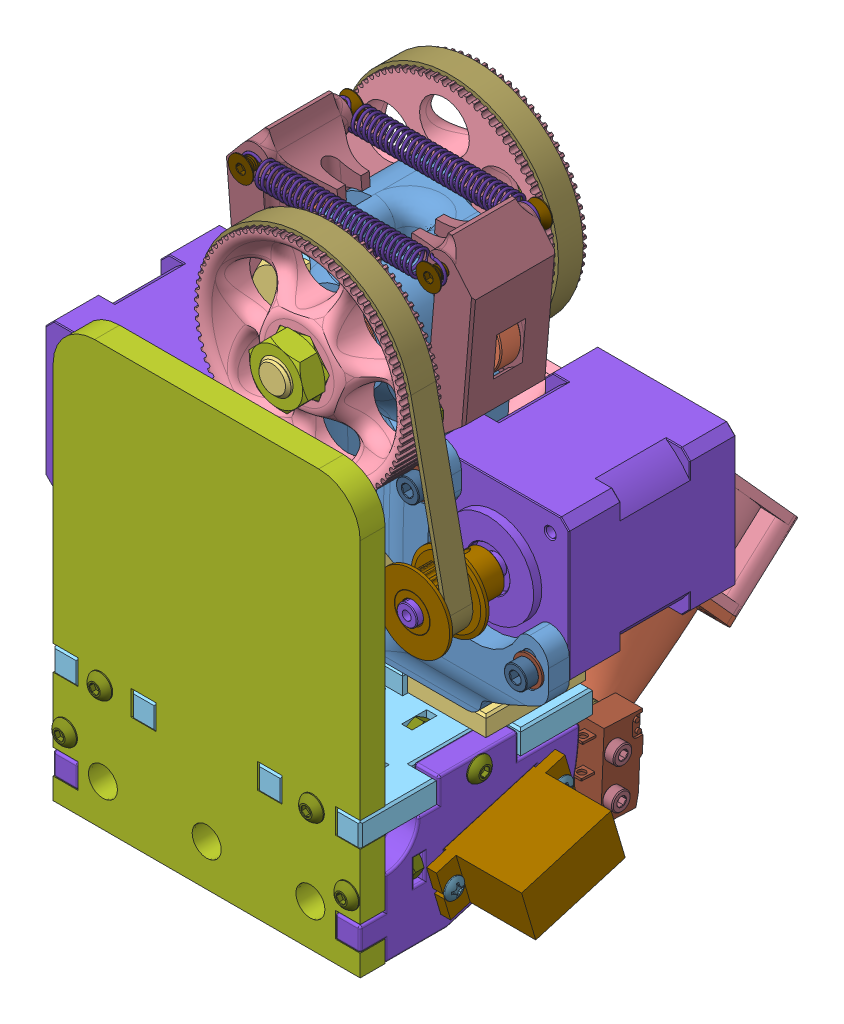
SolidWorks assembly XCarriageAssembly, configuration Default. Lengths in mm.
Overall size (108.39 160.46 126.11).
101 component instances, 38 part files, 22 mates.
Components (placement in the parent):
- IttyBittyDoubleExtruderAssembly-1: IttyBittyDoubleExtruderAssembly [Default] at origin size (106.39 98.03 74.25)
  - IttyBittyDoubleExtruderBlock-1: IttyBittyDoubleExtruderBlock [Default] at origin size (106.2 79.3 54.92)
  - Bearing-688-1: Bearing-688 [7804K117] at (-8 64.4888 10.5) size (16 16 5)
  - Bearing-688-2: Bearing-688 [7804K117] at (8 64.4888 16.5) size (16 16 5)
  - Bearing-688-3: Bearing-688 [7804K117] at (8 64.4888 -10.5) size (16 16 5)
  - Bearing-688-4: Bearing-688 [7804K117] at (-8 64.4888 -16.5) size (16 16 5)
  - HobbedBolt-1: HobbedBolt [Default] at (8 64.4888 -14) x (0.945139 -0.326669 0) z (0 0 1) size (14.66 12.7 56.13)
  - Parametric-Pulley-80-8-hex-1: Parametric-Pulley-80-8-hex [Default] at (8 64.4888 32) x (0.986927 0.161169 0) z (0 0 -1) size (50.4 50.4 9.47)
  - Spacer 1mm-1: Spacer 1mm [Default] at (8 64.4888 -14) size (13 13 1)
  - Spacer 2mm-1: Spacer 2mm [Default] at (8 64.4888 19) size (13 13 2)
  - HobbedBolt-2: HobbedBolt [Default] at (-8 64.4888 14) x (-0.397408 -0.917642 0) z (0 0 -1) size (14.66 12.7 56.13)
  - Parametric-Pulley-80-8-hex-2: Parametric-Pulley-80-8-hex [Default] at (-8 64.4888 -32) x (1 0 0) z (0 0 1) size (50.4 50.4 9.47)
  - Spacer 1mm-2: Spacer 1mm [Default] at (-8 64.4888 14) x (-0.923728 -0.383049 0) z (0 0 -1) size (13 13 1)
  - Spacer 2mm-2: Spacer 2mm [Default] at (-8 64.4888 -21) size (13 13 2)
  - 5-16-Nut-1: 5-16-Nut [Default] at (-8 64.4888 -30.3) size (14.66 12.7 5.2)
  - 5-16-Nut-2: 5-16-Nut [Default] at (8 64.4888 25.1) x (0.353886 0.935288 0) z (0 0 1) size (14.66 12.7 5.2)
  - 5-16-Nut-3: 5-16-Nut [Default] at (8 64.4888 30.3) x (0.969294 -0.245906 0) z (0 0 1) size (14.66 12.7 5.2)
  - 5-16-Nut-4: 5-16-Nut [Default] at (-8 64.4888 -35.5) x (0.948708 -0.316153 0) z (0 0 1) size (14.66 12.7 5.2)
  - NEMA14 Stepper Motor-1: NEMA14 Stepper Motor [Default] at (17.9692 8.8788 -30.1574) x (-1 0 0) z (0 1 0) size (36.32 61.75 35.05)
  - GT2_20tooth-1: GT2_20tooth [Default] at (35.4952 26.4048 12.75) x (0 0 1) z (-0.834274 -0.551351 0) size (17.5 18 18)
  - GT2_20tooth-2: GT2_20tooth [Default] at (-35.4952 26.4048 -12.75) x (0 0 -1) z (0.834274 -0.551351 0) size (17.5 18 18)
  - NEMA14 Stepper Motor-2: NEMA14 Stepper Motor [Default] at (-17.9692 8.8788 30.1574) x (1 0 0) z (0 1 0) size (36.32 61.75 35.05)
  - M3x10HexCapScrew-1: M3x10HexCapScrew [91290A115] at (22.5 13.4 5.45) x (-0.709862 0.70434 0) z (0 0 -1) size (5.5 5.5 13.21)
  - M3Washer-1: M3Washer [91166A210] at (22.5 13.4 15) x (0.895294 -0.445476 0) z (0 0 -1) size (7 7 0.45)
  - M3Washer-12: M3Washer [91166A210] at (-22.5 13.4 -15) x (-0.895294 -0.445476 0) z (0 0 1) size (7 7 0.45)
  - M3x10HexCapScrew-5: M3x10HexCapScrew [91290A115] at (-22.5 13.4 -5.45) x (0.709862 0.70434 0) z (0 0 1) size (5.5 5.5 13.21)
  - M3Washer-13: M3Washer [91166A210] at (22.5 39.4 15) x (0.895294 -0.445476 0) z (0 0 -1) size (7 7 0.45)
  - M3Washer-14: M3Washer [91166A210] at (48.5 13.4 15) x (0.895294 -0.445476 0) z (0 0 -1) size (7 7 0.45)
  - M3x10HexCapScrew-6: M3x10HexCapScrew [91290A115] at (22.5 39.4 5.45) x (-0.709862 0.70434 0) z (0 0 -1) size (5.5 5.5 13.21)
  - M3x10HexCapScrew-7: M3x10HexCapScrew [91290A115] at (48.5 13.4 5.45) x (-0.709862 0.70434 0) z (0 0 -1) size (5.5 5.5 13.21)
  - M3Washer-16: M3Washer [91166A210] at (-22.5 39.4 -15) x (-0.895294 -0.445476 0) z (0 0 1) size (7 7 0.45)
  - M3Washer-17: M3Washer [91166A210] at (-48.5 13.4 -15) x (-0.895294 -0.445476 0) z (0 0 1) size (7 7 0.45)
  - M3x10HexCapScrew-9: M3x10HexCapScrew [91290A115] at (-22.5 39.4 -5.45) x (0.709862 0.70434 0) z (0 0 1) size (5.5 5.5 13.21)
  - M3x10HexCapScrew-10: M3x10HexCapScrew [91290A115] at (-48.5 13.4 -5.45) x (0.709862 0.70434 0) z (0 0 1) size (5.5 5.5 13.21)
  - DriveBelt-1: DriveBelt [Default] at (0 0 25.5) x (-1 0 0) z (0 0 -1) size (60.34 70.93 6)
  - DriveBelt-2: DriveBelt [Default] at (0 0 -25.5) size (60.34 70.93 6)
  - IdlerBlock-1: IdlerBlock [Default] at (21.104 63.5553 0) x (-0.996453 0.084148 0) z (0 0 -1) size (20.98 41.13 20.11)
  - Bearing-688-5: Bearing-688 [7804K117] at (21.104 63.5553 0) x (0.754304 -0.656525 0) z (0 0 1) size (16 16 5)
  - IdlerPin-15mm-1: IdlerPin-15mm [Default] at (21.104 63.5553 0) x (-0.996453 0.084148 0) z (0 0 1) size (7.5 8 15.6)
  - M3x25-1: M3x25 [91290A125] at (20.0438 51 15) x (0.098651 -0.995122 0) z (0 0 1) size (5.5 5.5 28.26)
  - M3HexNut-1: M3HexNut [90591A121] at (20.0438 51 11.2) x (0.996239 -0.086644 0) z (-0.086644 -0.996239 0) size (5.5 2.58 6.35)
  - M3HexNut-2: M3HexNut [90591A121] at (-20.0438 51 -11.2) x (-0.996239 -0.086644 0) z (0.086644 -0.996239 0) size (5.5 2.58 6.35)
  - M3x25-2: M3x25 [91290A125] at (-20.0438 51 -15) x (-0.098651 -0.995122 0) z (0 0 -1) size (5.5 5.5 28.26)
  - IdlerPin-15mm-2: IdlerPin-15mm [Default] at (-21.104 63.5553 0) x (0.996453 0.084148 0) z (0 0 -1) size (7.5 8 15.6)
  - Bearing-688-6: Bearing-688 [7804K117] at (-21.104 63.5553 0) x (-0.754304 -0.656525 0) z (0 0 -1) size (16 16 5)
  - IdlerBlock-2: IdlerBlock [Default] at (-21.104 63.5553 0) x (0.996453 0.084148 0) z (0 0 1) size (20.98 41.13 20.11)
  - ExtensionSpring-1: ExtensionSpring [extended] at (-62.7334 81.5024 -11.4843) size (49.53 5.74 5.79)
  - ExtensionSpring-2: ExtensionSpring [extended] at (62.7334 81.5024 11.4843) x (-1 0 0) z (0 0 -1) size (49.53 5.74 5.79)
  - M3x12HexFlatScrew-1: M3x12HexFlatScrew [92125A132] at (22.6187 81.4915 -13.5) x (0.115685 0.993286 0) z (0 0 -1) size (6 6 12.31)
  - M3x12HexFlatScrew-2: M3x12HexFlatScrew [92125A132] at (22.6188 81.4921 13.5) x (-0.115685 -0.993286 0) z (0 0 1) size (6 6 12.31)
  - M3x12HexFlatScrew-3: M3x12HexFlatScrew [92125A132] at (-22.6188 81.4921 -13.5) x (0.115685 -0.993286 0) z (0 0 -1) size (6 6 12.31)
  - M3x12HexFlatScrew-4: M3x12HexFlatScrew [92125A132] at (-22.6187 81.4915 13.5) x (-0.115685 0.993286 0) z (0 0 1) size (6 6 12.31)
  - M3HexNut-3: M3HexNut [90591A121] at (0 1.2 7.5) x (0.866025 0 -0.5) z (0.5 0 0.866025) size (5.5 2.58 6.35)
  - M3HexNut-4: M3HexNut [90591A121] at (0 1.2 -7.5) x (0.866025 0 0.5) z (-0.5 0 0.866025) size (5.5 2.58 6.35)
  - M4HexNut-1: M4HexNut [91828A231] at (-24.875 1.6 0) x (0 0 -1) z (1 0 0) size (7 3.44 8.08)
  - M4HexNut-2: M4HexNut [91828A231] at (24.875 1.6 0) x (0 0 -1) z (1 0 0) size (7 3.44 8.08)
- PartCoolingDoubleFanShroud-1: PartCoolingDoubleFanShroud [Default] at (0 -16.3003 -51.7968) x (1 0 0) z (0 -0.742562 -0.669777) size (41.23 51.54 53.9)
- DoubleGrooveMount-1: DoubleGrooveMount [Default] at (0 -9.6 0) x (-1 0 0) z (0 0 -1) size (70 5.31 24)
- 40x40x20Fan-1: 40x40x20Fan [Default] at (0 -16.3003 -51.7968) x (1 0 0) z (0 0.669777 -0.742562) size (40 40 20)
- XCarriageShelfAssembly-1: XCarriageShelfAssembly [Default] at (0 -9.6 38.3) size (93.97 101.26 108.07) (flexible)
  - XCarriageDoubleShelf-1: XCarriageDoubleShelf [Default] at (-37 0 -50) x (1 0 0) z (0 0 -1) size (74 10.95 56)
  - 25x25x10Fan-1: 25x25x10Fan [Default] at (-0.033 8 -12.717) x (1 0 0) z (0 -1 0) size (25 25 10)
  - XCarriageBackPlate-1: XCarriageBackPlate [Default] at (-37 -32.5 0) size (74 101.26 6)
  - ServoShelfBracket-1: ServoShelfBracket [Hot End Wiring Vent] at (-31 -6 0) x (0 0 -1) z (1 0 0) size (53 32.5 6)
  - ServoShelfBracket-2: ServoShelfBracket [HXT900] at (37 -6 0) x (0 0 -1) z (1 0 0) size (53 32.5 6)
  - Servo-HXT900-1: Servo-HXT900 [Default] at (55.2 -23.6377 -24.0991) x (0 -0.284598 0.958647) z (-1 0 0) size (32.3 12 29.6)
  - ZProbeAssembly-2: ZProbeAssembly [Default] at (38.1869 -30.9211 -29.7972) x (0 -0.042074 -0.999115) z (0 0.999115 -0.042074) size (39.46 14.76 19.99)
    - Servo Horn-1: Servo Horn [Default] at (34.2536 11.8969 23.9402) size (19.66 4.12 7.35)
    - SnapLimitSwitch-1: SnapLimitSwitch [Default] at (22.9628 5.2957 11.2222) x (0.000181 0 -1) z (0 -1 0) size (19.99 14.86 6.5)
    - ZProbeArmMirrored-1: ZProbeArmMirrored [Default] at (-0.0025 17.1137 27.8606) x (1 0 0.000181) z (0.000181 0 -1) size (33.66 4.95 19.95)
    - M2.5x10HexSocketScrew-1: M2.5x10HexSocketScrew [91292A014] at (25.3259 12.0445 6.4347) x (-0.001575 0 0.999999) z (0 1 0) size (4.5 4.5 13.01)
    - M2.5x10HexSocketScrew-2: M2.5x10HexSocketScrew [91292A014] at (25.3241 12.0445 15.9347) x (-0.043466 0 0.999055) z (0 1 0) size (4.5 4.5 13.01)
    - ServoScrew-1: ServoScrew [93406A071] at (1.841 12.5869 13.9305) x (0.770997 0 -0.636839) z (0 1 0) size (4.93 5.18 10.49)
  - TightDoubleHexagonShroud-1: TightDoubleHexagonShroud [No Support] at (0 -6 0) x (1 0 0) z (0 0 -1) size (57.71 23.73 44.86)
  - M3HexNut-1: M3HexNut [90591A121] at (25.5 -3 -8.2) x (0.5 -0.866025 0) z (-0.866025 -0.5 0) size (5.5 2.58 6.35)
  - M3HexNut-2: M3HexNut [90591A121] at (-25.5 -3 -8.2) x (0.5 0.866025 0) z (0.866025 -0.5 0) size (5.5 2.58 6.35)
  - M3HexNut-3: M3HexNut [90591A121] at (22.8 -3 -22.5) x (0 0.866025 -0.5) z (0 -0.5 -0.866025) size (5.5 2.58 6.35)
  - M3HexNut-4: M3HexNut [90591A121] at (34 -17 -8.2) x (0 -1 0) z (-1 0 0) size (5.5 2.58 6.35)
  - M3HexNut-5: M3HexNut [90591A121] at (-22.8 -3 -22.5) x (0 0 1) z (0 -1 0) size (5.5 2.58 6.35)
  - M3HexNut-6: M3HexNut [90591A121] at (-34 -17 -8.2) x (0.866025 -0.5 0) z (-0.5 -0.866025 0) size (5.5 2.58 6.35)
  - M3x16HexButtonScrew-1: M3x16HexButtonScrew [92095A184] at (-34 -16.66 7.65) x (-0.903023 -0.429591 0) z (0 0 1) size (5.7 5.7 18)
  - M3x16HexButtonScrew-2: M3x16HexButtonScrew [92095A184] at (34 -16.66 7.65) x (-0.860108 -0.510112 0) z (0 0 1) size (5.7 5.7 18)
  - M3x16HexButtonScrew-3: M3x16HexButtonScrew [92095A184] at (-38.65 -3 -22.5) x (0 0 -1) z (-1 0 0) size (5.7 5.7 18)
  - M3x16HexButtonScrew-4: M3x16HexButtonScrew [92095A184] at (-25.5 -2.66 7.65) x (-0.902268 -0.431175 0) z (0 0 1) size (5.7 5.7 18)
  - M3x16HexButtonScrew-5: M3x16HexButtonScrew [92095A184] at (25.5 -2.66 7.65) x (-0.990562 0.137069 0) z (0 0 1) size (5.7 5.7 18)
  - M3x16HexButtonScrew-6: M3x16HexButtonScrew [92095A184] at (38.65 -3 -22.5) x (0 0 1) z (1 0 0) size (5.7 5.7 18)
  - ServoScrew-1: ServoScrew [93406A071] at (39.4 -22.4735 -14.0563) x (0 0 1) z (1 0 0) size (4.93 5.18 10.49)
  - ServoScrew-2: ServoScrew [93406A071] at (39.4 -14.6755 -40.3232) x (0 0 1) z (1 0 0) size (4.93 5.18 10.49)
  - M3x6HexButtonScrew-1: M3x6HexButtonScrew [92095A179] at (-20 -8.85 -15) x (0.503346 0 0.864085) z (0 -1 0) size (5.7 5.7 7.94)
  - M3x6HexButtonScrew-2: M3x6HexButtonScrew [92095A179] at (20 -8.85 -15) x (0.401704 0 0.915769) z (0 -1 0) size (5.7 5.7 7.94)
  - M3x12HexFlatScrew-1: M3x12HexFlatScrew [92125A132] at (-10.033 -6 -2.717) x (0.401704 0 0.915769) z (0 -1 0) size (6 6 12.31)
  - M3x12HexFlatScrew-2: M3x12HexFlatScrew [92125A132] at (9.967 -6 -22.717) x (0.401704 0 0.915769) z (0 -1 0) size (6 6 12.31)
  - M3x12HexFlatScrew-3: M3x12HexFlatScrew [92125A132] at (9.967 -6 -2.717) x (0.401704 0 0.915769) z (0 -1 0) size (6 6 12.31)
- M3x20-1: M3x20 [92290A122] at (12.5 0.4 -30) x (0 0 -1) z (1 0 0) size (5.5 5.5 23.58)
- M3HexNut-1: M3HexNut [90591A121] at (8.7 0.4 -30) x (0 -1 0) z (0 0 1) size (5.5 2.58 6.35)
- HexagonAssembled-1: HexagonAssembled [Default] at (-3.9618 -43.6544 0.5889) x (-0.982838 0 0.184472) z (-0.184472 0 -0.982838) size (20 54.51 24.04)
  - HexagonHotEnd-1: HexagonHotEnd [Default] at (-13.8308 34.4544 -1.9967) size (16 54.51 22.04)
  - HexagonBlockInsulator-1: HexagonBlockInsulator [Default] at origin size (20 12.11 22)
- HexagonAssembled-2: HexagonAssembled [Default] at (-10.6362 -43.6544 -13.9597) x (-0.187796 0 -0.982208) z (0.982208 0 -0.187796) size (20 54.51 24.04)
  - HexagonHotEnd-1: HexagonHotEnd [Default] at (-13.8308 34.4544 -1.9967) size (16 54.51 22.04)
  - HexagonBlockInsulator-1: HexagonBlockInsulator [Default] at origin size (20 12.11 22)
Mates (geometry in assembly coordinates):
- Coincident1: coincident aligned: plane of IttyBittyDoubleExtruderAssembly-1/IttyBittyDoubleExtruderBlock-1 through (0 0 0) normal (0 1 0); plane of assembly through (0 0 0) normal (0 1 0)
- Coincident2: coincident aligned: plane of IttyBittyDoubleExtruderAssembly-1/IttyBittyDoubleExtruderBlock-1 through (0 0 0) normal (1 0 0); plane of assembly through (0 0 0) normal (1 0 0)
- Coincident3: coincident aligned: plane of IttyBittyDoubleExtruderAssembly-1/IttyBittyDoubleExtruderBlock-1 through (0 0 0) normal (0 0 1); plane of assembly through (0 0 0) normal (0 0 1)
- Concentric1: concentric aligned: cylinder of IttyBittyDoubleExtruderAssembly-1/IttyBittyDoubleExtruderBlock-1 through (4.4 0.4 -30) axis (-1 0 0) radius 1.7; cylinder of PartCoolingDoubleFanShroud-1 through (21.1857 0.4 -30) axis (-1 0 0) radius 1.7
- Coincident4: coincident aligned: plane of PartCoolingDoubleFanShroud-1; plane of assembly through (0 0 0) normal (1 0 0)
- Coincident12: coincident anti-aligned: plane of IttyBittyDoubleExtruderAssembly-1/IttyBittyDoubleExtruderBlock-1 through (0 -4.6 0) normal (0 -1 0); plane of DoubleGrooveMount-1 through (0 -4.6 0) normal (0 1 0)
- Coincident14: coincident anti-aligned: plane of PartCoolingDoubleFanShroud-1 through (0 -16.3003 -51.7968) normal (0 0.669777 -0.742562); plane of 40x40x20Fan-1 through (16 -4.4193 -41.0804) normal (0 -0.669777 0.742562)
- Concentric5: concentric anti-aligned: cylinder of PartCoolingDoubleFanShroud-1 through (-16 -5.7589 -39.5952) axis (0 0.669777 -0.742562) radius 1.2; cylinder of 40x40x20Fan-1 through (-16 8.9762 -55.9316) axis (0 -0.669777 0.742562) radius 1.905
- Concentric6: concentric anti-aligned: cylinder of PartCoolingDoubleFanShroud-1 through (16 -29.5208 -61.0281) axis (0 0.669777 -0.742562) radius 1.2; cylinder of 40x40x20Fan-1 through (16 -14.7857 -77.3645) axis (0 -0.669777 0.742562) radius 1.905
- Parallel5: parallel anti-aligned: plane of DoubleGrooveMount-1 through (0 -4.6 -12) normal (0 0 -1); plane of assembly through (0 0 0) normal (0 0 1)
- Concentric17: concentric anti-aligned: cylinder of PartCoolingDoubleFanShroud-1 through (21.1857 0.4 -30) axis (-1 0 0) radius 1.7; cylinder of M3x20-1 through (-10.5 0.4 -30) axis (1 0 0) radius 2.75
- Coincident39: coincident anti-aligned: plane of PartCoolingDoubleFanShroud-1 through (-7.5 -371297.3539 -334940.404) normal (-1 0 0); plane of M3x20-1 through (-7.5 0.4 -30) normal (1 0 0)
- Coincident41: coincident anti-aligned: plane of PartCoolingDoubleFanShroud-1 through (7.5 -371297.3539 -334940.404) normal (1 0 0); plane of M3HexNut-1 through (7.5 -2.35 -31.5877) normal (-1 0 0)
- Concentric18: concentric anti-aligned: cylinder of M3x20-1 through (-10.5 0.4 -30) axis (1 0 0) radius 2.75; circle of M3HexNut-1
- Coincident44: coincident anti-aligned: plane of DoubleGrooveMount-1 through (10 -9.2 0) normal (0 -1 0); plane of HexagonAssembled-1/HexagonHotEnd-1 through (10 -9.2 0) normal (0 1 0)
- Concentric20: concentric aligned: cylinder of DoubleGrooveMount-1 through (10 -4.6 0) axis (0 -1 0) radius 6.075; cylinder of HexagonAssembled-1/HexagonHotEnd-1 through (10 -4.56 0) axis (0 -1 0) radius 6
- Coincident45: coincident anti-aligned: plane of DoubleGrooveMount-1 through (-10 -9.2 0) normal (0 -1 0); plane of HexagonAssembled-2/HexagonHotEnd-1 through (-10 -9.2 0) normal (0 1 0)
- Concentric21: concentric aligned: cylinder of DoubleGrooveMount-1 through (-10 -4.6 0) axis (0 -1 0) radius 6.075; cylinder of HexagonAssembled-2/HexagonHotEnd-1 through (-10 -4.56 0) axis (0 -1 0) radius 6
- Concentric22: concentric anti-aligned: cylinder of IttyBittyDoubleExtruderAssembly-1/IttyBittyDoubleExtruderBlock-1 through (-10 -4.6 0) axis (0 1 0) radius 8.5; cylinder of HexagonAssembled-2/HexagonHotEnd-1 through (-10 0.2 0) axis (0 -1 0) radius 8
- Coincident60: coincident anti-aligned: plane of DoubleGrooveMount-1 through (0 -9.6 0) normal (0 -1 0); plane of XCarriageShelfAssembly-1/XCarriageDoubleShelf-1 through (-37 -9.6 -11.7) normal (0 1 0)
- Concentric27: concentric anti-aligned: cylinder of DoubleGrooveMount-1 through (-24.875 -4.6 0) axis (0 -1 0) radius 2.5; cylinder of XCarriageShelfAssembly-1/XCarriageDoubleShelf-1 through (-24.875 -15.6 0) axis (0 1 0) radius 2.2
- Concentric28: concentric anti-aligned: cylinder of DoubleGrooveMount-1 through (24.875 -4.6 0) axis (0 -1 0) radius 2.5; cylinder of XCarriageShelfAssembly-1/XCarriageDoubleShelf-1 through (24.875 -15.6 0) axis (0 1 0) radius 2.2
